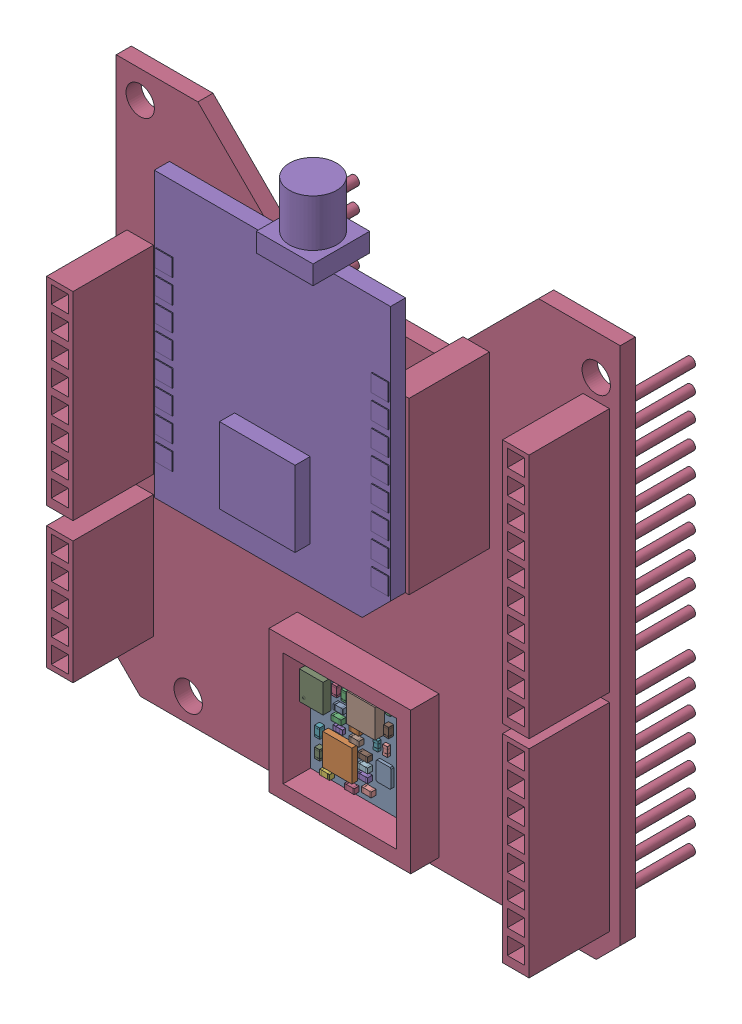
SolidWorks assembly MTi-1_v3, configuration Default. Lengths in mm.
Overall size (53.34 66.07 22.31).
57 component instances, 28 part files, 0 mates.
Components (placement in the parent):
- Board_1v2(2)^MTi-1-SoB_v2-1: Board_1v2(2)^MTi-1-SoB_v2 [Default] at origin size (12.15 12.15 1.56)
  - Open CASCADE STEP translator 6.8 2.1.1^Board_1v2(2)_MTi-1-SoB_v2-1: Open CASCADE STEP translator 6.8 2.1.1^Board_1v2(2)_MTi-1-SoB_v2 [Default] at (0 0 -1.5563) size (12.15 12.15 1.56)
    - Open CASCADE STEP translator 6.8 2.1.1.1^Open CASCADE STEP translator_ 6.8 2.1.1_Board_1v2(2)_MTi-1-SoB_v2-1: Open CASCADE STEP translator 6.8 2.1.1.1^Open CASCADE STEP translator_ 6.8 2.1.1_Board_1v2(2)_MTi-1-SoB_v2 [Default] at origin size (12.15 12.15 1.56)
- U200_1v2(2)^MTi-1-SoB_v2-1: U200_1v2(2)^MTi-1-SoB_v2 [Default] at origin size (3.1 3.3 0.6)
  - 7460079024(2)^U200_1v2(2)_MTi-1-SoB_v2-1: 7460079024(2)^U200_1v2(2)_MTi-1-SoB_v2 [Default] at (5.6 3.4 0) size (3.1 3.3 0.6)
    - Extruded(2)^7460079024(2)_U200_1v2(2)_MTi-1-SoB_v2-1: Extruded(2)^7460079024(2)_U200_1v2(2)_MTi-1-SoB_v2 [Default] at origin size (3.1 3.3 0.6)
- C200_1v2(2)^MTi-1-SoB_v2-1: C200_1v2(2)^MTi-1-SoB_v2 [Default] at origin size (1.05 0.55 0.55)
  - Cap_0402(2)^C200_1v2(2)_MTi-1-SoB_v2-1: Cap_0402(2)^C200_1v2(2)_MTi-1-SoB_v2 [Default] at (5.3999 6.9749 0.26) x (-1 0 0) z (0 0 1) size (1.05 0.55 0.55)
- C201_1v2(2)^MTi-1-SoB_v2-1: C201_1v2(2)^MTi-1-SoB_v2 [Default] at origin size (1.05 0.55 0.55)
  - Cap_0402(2)^C201_1v2(2)_MTi-1-SoB_v2-1: Cap_0402(2)^C201_1v2(2)_MTi-1-SoB_v2 [Default] at (6.7999 1.375 0.26) x (-1 0 0) z (0 0 1) size (1.05 0.55 0.55)
- C204_1v2(2)^MTi-1-SoB_v2-1: C204_1v2(2)^MTi-1-SoB_v2 [Default] at origin size (1.05 0.55 0.55)
  - Cap_0402(2)^C204_1v2(2)_MTi-1-SoB_v2-1: Cap_0402(2)^C204_1v2(2)_MTi-1-SoB_v2 [Default] at (8.1999 3.0749 0.26) x (-1 0 0) z (0 0 1) size (1.05 0.55 0.55)
- C205_1v2(2)^MTi-1-SoB_v2-1: C205_1v2(2)^MTi-1-SoB_v2 [Default] at origin size (1.05 0.55 0.55)
  - Cap_0402(2)^C205_1v2(2)_MTi-1-SoB_v2-1: Cap_0402(2)^C205_1v2(2)_MTi-1-SoB_v2 [Default] at (4.2001 0.8251 0.26) x (1 0 0) z (0 0 1) size (1.05 0.55 0.55)
- C206_1v2(2)^MTi-1-SoB_v2-1: C206_1v2(2)^MTi-1-SoB_v2 [Default] at origin size (0.55 1.05 0.55)
  - Cap_0402(2)^C206_1v2(2)_MTi-1-SoB_v2-1: Cap_0402(2)^C206_1v2(2)_MTi-1-SoB_v2 [Default] at (3.1251 4.5999 0.26) x (0 -1 0) z (0 0 1) size (1.05 0.55 0.55)
- C207_1v2(2)^MTi-1-SoB_v2-1: C207_1v2(2)^MTi-1-SoB_v2 [Default] at origin size (1.05 0.55 0.55)
  - Cap_0402(2)^C207_1v2(2)_MTi-1-SoB_v2-1: Cap_0402(2)^C207_1v2(2)_MTi-1-SoB_v2 [Default] at (7.3001 5.4251 0.26) x (1 0 0) z (0 0 1) size (1.05 0.55 0.55)
- C208_1v2(2)^MTi-1-SoB_v2-1: C208_1v2(2)^MTi-1-SoB_v2 [Default] at origin size (0.55 1.05 0.55)
  - Cap_0402(2)^C208_1v2(2)_MTi-1-SoB_v2-1: Cap_0402(2)^C208_1v2(2)_MTi-1-SoB_v2 [Default] at (3.1251 2.5999 0.26) x (0 -1 0) z (0 0 1) size (1.05 0.55 0.55)
- C209_1v2(2)^MTi-1-SoB_v2-1: C209_1v2(2)^MTi-1-SoB_v2 [Default] at origin size (1.05 0.55 0.55)
  - Cap_0402(2)^C209_1v2(2)_MTi-1-SoB_v2-1: Cap_0402(2)^C209_1v2(2)_MTi-1-SoB_v2 [Default] at (8.6001 1.4251 0.26) x (1 0 0) z (0 0 1) size (1.05 0.55 0.55)
- C300_1v2(2)^MTi-1-SoB_v2-1: C300_1v2(2)^MTi-1-SoB_v2 [Default] at origin size (0.55 1.05 0.55)
  - Cap_0402(2)^C300_1v2(2)_MTi-1-SoB_v2-1: Cap_0402(2)^C300_1v2(2)_MTi-1-SoB_v2 [Default] at (10.425 8.2999 0.26) x (0 -1 0) z (0 0 1) size (1.05 0.55 0.55)
- C301_1v2(2)^MTi-1-SoB_v2-1: C301_1v2(2)^MTi-1-SoB_v2 [Default] at origin size (1.05 0.55 0.55)
  - Cap_0402(2)^C301_1v2(2)_MTi-1-SoB_v2-1: Cap_0402(2)^C301_1v2(2)_MTi-1-SoB_v2 [Default] at (3.4001 10.375 0.26) x (1 0 0) z (0 0 1) size (1.05 0.55 0.55)
- C302_1v2(2)^MTi-1-SoB_v2-1: C302_1v2(2)^MTi-1-SoB_v2 [Default] at origin size (1.05 0.55 0.55)
  - Cap_0402(2)^C302_1v2(2)_MTi-1-SoB_v2-1: Cap_0402(2)^C302_1v2(2)_MTi-1-SoB_v2 [Default] at (5.5999 8.0749 0.26) x (-1 0 0) z (0 0 1) size (1.05 0.55 0.55)
- C303_1v2(2)^MTi-1-SoB_v2-1: C303_1v2(2)^MTi-1-SoB_v2 [Default] at origin size (1.05 0.55 0.55)
  - Cap_0402(2)^C303_1v2(2)_MTi-1-SoB_v2-1: Cap_0402(2)^C303_1v2(2)_MTi-1-SoB_v2 [Default] at (7.2999 6.9749 0.26) x (-1 0 0) z (0 0 1) size (1.05 0.55 0.55)
- C305_1v2(2)^MTi-1-SoB_v2-1: C305_1v2(2)^MTi-1-SoB_v2 [Default] at origin size (0.55 1.05 0.55)
  - Cap_0402(2)^C305_1v2(2)_MTi-1-SoB_v2-1: Cap_0402(2)^C305_1v2(2)_MTi-1-SoB_v2 [Default] at (6.4749 9.3001 0.26) x (0 1 0) z (0 0 1) size (1.05 0.55 0.55)
- C304_1v2(2)^MTi-1-SoB_v2-1: C304_1v2(2)^MTi-1-SoB_v2 [Default] at origin size (0.55 1.05 0.55)
  - Cap_0402(2)^C304_1v2(2)_MTi-1-SoB_v2-1: Cap_0402(2)^C304_1v2(2)_MTi-1-SoB_v2 [Default] at (5.4749 9.3001 0.26) x (0 1 0) z (0 0 1) size (1.05 0.55 0.55)
- R200_1v2(2)^MTi-1-SoB_v2-1: R200_1v2(2)^MTi-1-SoB_v2 [Default] at origin size (1 0.5 0.35)
  - RES0402(2)^R200_1v2(2)_MTi-1-SoB_v2-1: RES0402(2)^R200_1v2(2)_MTi-1-SoB_v2 [Default] at (-16.787 18.2331 0) x (-1 0 0) z (0 1 0) size (1 0.35 0.5)
- R300_1v2(2)^MTi-1-SoB_v2-1: R300_1v2(2)^MTi-1-SoB_v2 [Default] at origin size (0.5 1 0.35)
  - RES0402(2)^R300_1v2(2)_MTi-1-SoB_v2-1: RES0402(2)^R300_1v2(2)_MTi-1-SoB_v2 [Default] at (13.6331 30.587 0) x (0 1 0) z (1 0 0) size (1 0.35 0.5)
- R301_1v2(2)^MTi-1-SoB_v2-1: R301_1v2(2)^MTi-1-SoB_v2 [Default] at origin size (0.5 1 0.35)
  - RES0402(2)^R301_1v2(2)_MTi-1-SoB_v2-1: RES0402(2)^R301_1v2(2)_MTi-1-SoB_v2 [Default] at (21.9331 28.487 0) x (0 1 0) z (1 0 0) size (1 0.35 0.5)
- S300_1v2(2)^MTi-1-SoB_v2-1: S300_1v2(2)^MTi-1-SoB_v2 [Default] at origin size (3 3 1)
  - 6752205952(2)^S300_1v2(2)_MTi-1-SoB_v2-1: 6752205952(2)^S300_1v2(2)_MTi-1-SoB_v2 [Default] at (8.4999 8.8999 0) size (3 3 1)
    - Extruded-1(2)^6752205952(2)_S300_1v2(2)_MTi-1-SoB_v2-1: Extruded-1(2)^6752205952(2)_S300_1v2(2)_MTi-1-SoB_v2 [Default] at origin size (3 3 1)
- S301_1v2(2)^MTi-1-SoB_v2-1: S301_1v2(2)^MTi-1-SoB_v2 [Default] at origin size (2.5 3 0.86)
  - User_Library-LGA-14_2_5x3(2)^S301_1v2(2)_MTi-1-SoB_v2-1: User_Library-LGA-14_2_5x3(2)^S301_1v2(2)_MTi-1-SoB_v2 [Default] at (3.1 8.3 0.85) x (0 -1 0) z (1 0 0) size (3 0.86 2.5)
- R302_1v2(2)^MTi-1-SoB_v2-1: R302_1v2(2)^MTi-1-SoB_v2 [Default] at origin size (0.5 1 0.35)
  - RES0402(2)^R302_1v2(2)_MTi-1-SoB_v2-1: RES0402(2)^R302_1v2(2)_MTi-1-SoB_v2 [Default] at (22.9331 28.487 0) x (0 1 0) z (1 0 0) size (1 0.35 0.5)
- C202_1v2(2)^MTi-1-SoB_v2-1: C202_1v2(2)^MTi-1-SoB_v2 [Default] at origin size (1.05 0.55 0.55)
  - Cap_0402(2)^C202_1v2(2)_MTi-1-SoB_v2-1: Cap_0402(2)^C202_1v2(2)_MTi-1-SoB_v2 [Default] at (8.2001 4.4251 0.26) x (1 0 0) z (0 0 1) size (1.05 0.55 0.55)
- C203_1v2(2)^MTi-1-SoB_v2-1: C203_1v2(2)^MTi-1-SoB_v2 [Default] at origin size (1.05 0.55 0.55)
  - Cap_0402(2)^C203_1v2(2)_MTi-1-SoB_v2-1: Cap_0402(2)^C203_1v2(2)_MTi-1-SoB_v2 [Default] at (8.2001 3.4251 0.26) x (1 0 0) z (0 0 1) size (1.05 0.55 0.55)
- Y200_1v2(2)^MTi-1-SoB_v2-1: Y200_1v2(2)^MTi-1-SoB_v2 [Default] at origin size (1.61 2.01 0.31)
  - User_Library-Crystal_(NDK)_2.0x1.6(2)^Y200_1v2(2)_MTi-1-SoB_v2-1: User_Library-Crystal_(NDK)_2.0x1.6(2)^Y200_1v2(2)_MTi-1-SoB_v2 [Default] at (10.2 4.0001 0) x (0 -1 0) z (-1 0 0) size (2.01 0.31 1.61)
- R303_1v2(2)^MTi-1-SoB_v2-1: R303_1v2(2)^MTi-1-SoB_v2 [Default] at origin size (0.5 1 0.35)
  - RES0402(2)^R303_1v2(2)_MTi-1-SoB_v2-1: RES0402(2)^R303_1v2(2)_MTi-1-SoB_v2 [Default] at (-1.8331 -11.987 0) x (0 -1 0) z (-1 0 0) size (1 0.35 0.5)
- Mti-7 development board-1: Mti-7 development board [Default] at (6.7227 17.82 -3.1563) x (1 0 0) z (0 -1 0) size (53.34 18.51 57.52)
- GNSS_board-1: GNSS_board [Default] at (6.6927 40.5245 6.9537) size (25 37 6)
